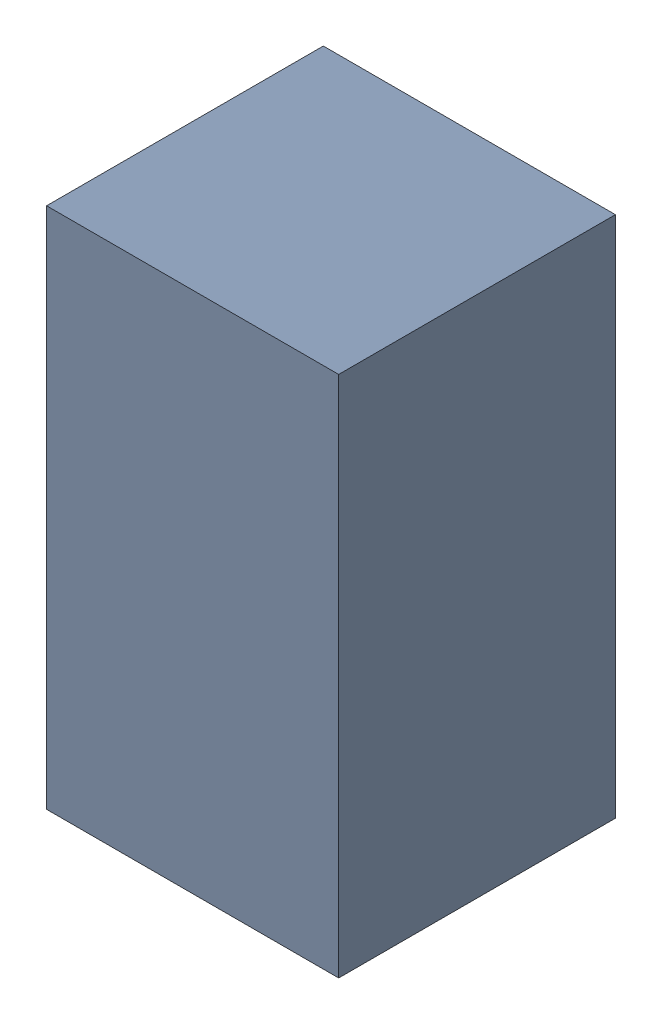
SolidWorks assembly R1_TDA4, configuration Standard. Lengths in mm.
Overall size (0.95 1.7 0.9).
2 component instances, 1 part files, 0 mates.
Components (placement in the parent):
- 885541560-1: 885541560 [Standard] at (6.18 -49.99 0) size (0.95 1.7 0.9)
  - Extruded_16-1: Extruded_16 [Standard] at origin size (0.95 1.7 0.9)
